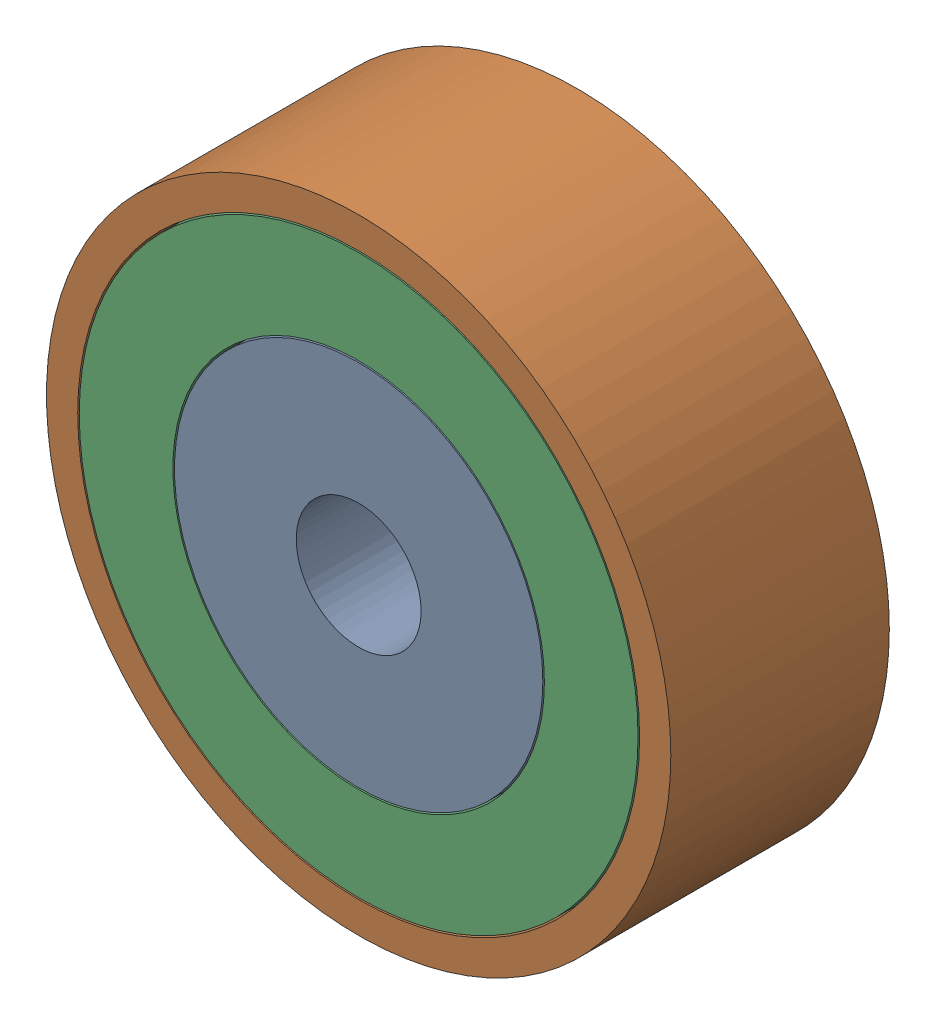
SolidWorks assembly 镜向轴承14, configuration 默认. Lengths in mm.
Overall size (20 20 7).
3 component instances, 3 part files, 4 mates.
Components (placement in the parent):
- 镜向轴承内圈-1: 镜向轴承内圈 [默认] at (-5.0655 0.8032 -6.5) size (11.8 11.8 7)
- 镜向轴承外圈-1: 镜向轴承外圈 [默认] at (-5.0655 0.8032 -6.5) size (20 20 7)
- 镜向轴承中圈-1: 镜向轴承中圈 [默认] at (-5.0655 0.8032 -6.5) size (17.9 17.9 7)
Mates (geometry in assembly coordinates):
- 重合1: coincident: plane of ? through (-5.0655 0.8032 -13.5) normal (0 0 -1); plane of ? through (-5.0655 0.8032 -13.5) normal (0 0 -1)
- 重合2: coincident: plane of ? through (-5.0655 0.8032 -13.5) normal (0 0 -1); plane of ? through (-5.0655 0.8032 -13.5) normal (0 0 -1)
- 同心1: concentric: cylinder of ? through (-5.0655 0.8032 -13.5) axis (0 0 1) radius 9; cylinder of ? through (-5.0655 0.8032 -13.5) axis (0 0 1) radius 8.95
- 同心2: concentric: cylinder of ? through (-5.0655 0.8032 -13.5) axis (0 0 1) radius 5.9; cylinder of ? through (-5.0655 0.8032 -13.5) axis (0 0 1) radius 5.95
